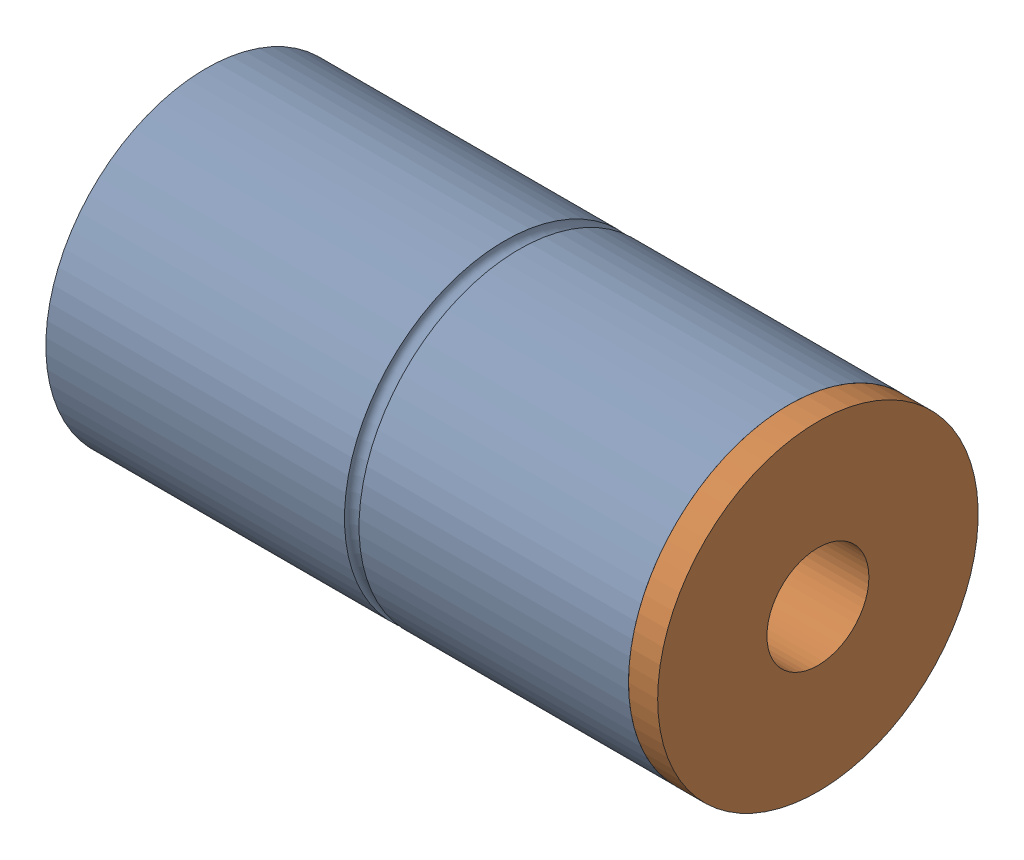
SolidWorks assembly Assem2, configuration Default. Lengths in mm.
Overall size (210 110 110).
2 component instances, 2 part files, 1 mates.
Components (placement in the parent):
- Part1-1: Part1 [Default] at (-60.0763 60.6074 199.4597) size (200 110 110)
- Part2-1: Part2 [Default] at (149.9237 60.6074 199.4597) x (-1 0 0) z (0 0 -1) size (200 110 110)
Mates (geometry in assembly coordinates):
- Coincident1: coincident aligned: circle of Part1-1; circle of Part2-1
